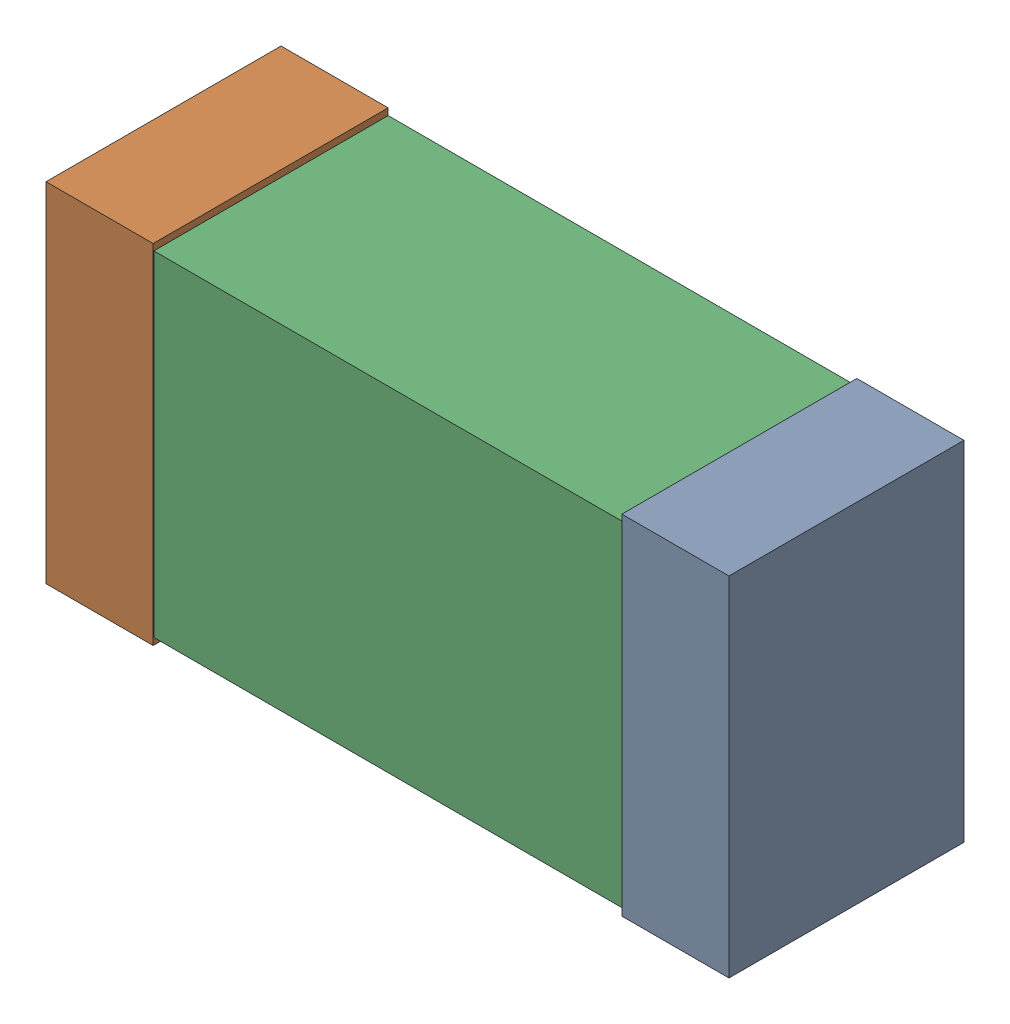
SolidWorks assembly C59, configuration Default. Lengths in mm.
Overall size (1.02 0.52 0.35).
6 component instances, 2 part files, 0 mates.
Components (placement in the parent):
- 870940480-1: 870940480 [Default] at (34.847 5.588 0) size (0.16 0.52 0.35)
  - Extruded-1: Extruded [Default] at origin size (0.16 0.52 0.35)
- 870940480-2: 870940480 [Default] at (33.987 5.588 0) size (0.16 0.52 0.35)
  - Extruded-1: Extruded [Default] at origin size (0.16 0.52 0.35)
- 870940640-1: 870940640 [Default] at (34.417 5.588 0) size (1 0.5 0.35)
  - Extruded_2-1: Extruded_2 [Default] at origin size (1 0.5 0.35)
